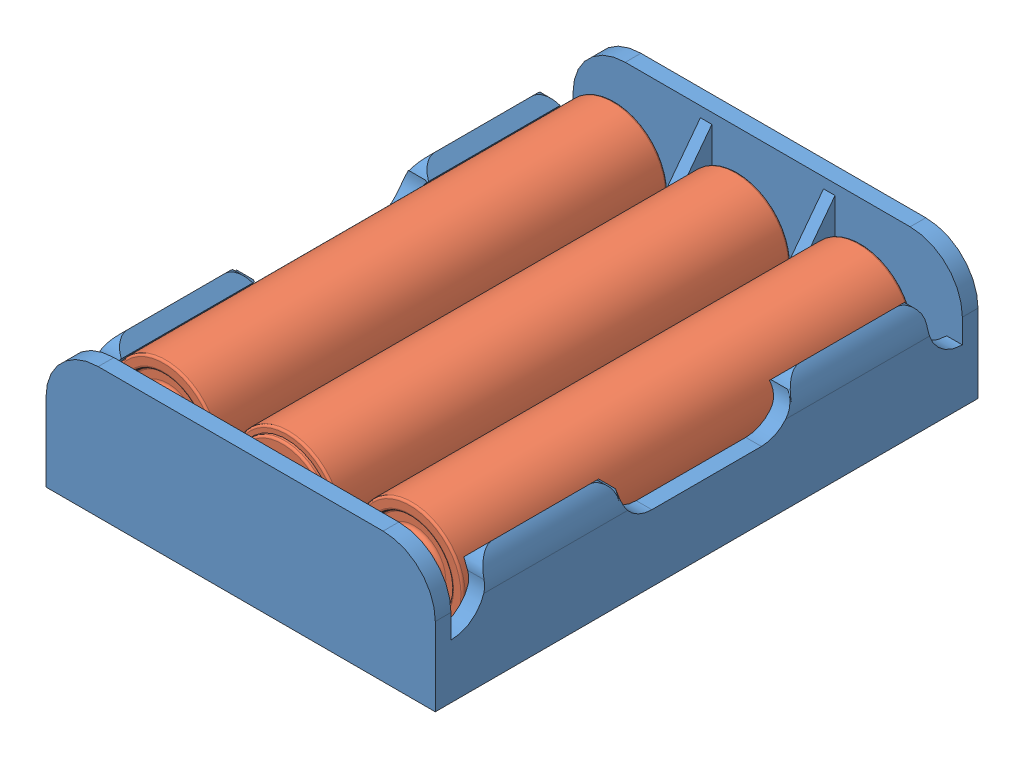
SolidWorks assembly Assemblage Coupleur piles, configuration Défaut. Lengths in mm.
Overall size (37.3 13.3 52).
4 component instances, 2 part files, 6 mates.
Components (placement in the parent):
- Coupleur piles-1: Coupleur piles [Défaut] at (3.7498 -7.3458 52) size (37.3 12.5 52)
- Pile-1: Pile [Défaut] at (-8.0261 -0.7458 30.4) x (0.997428 0.07167 0) z (0.07167 -0.997428 0) size (10.2 44.7 10.2)
- Pile-2: Pile [Défaut] at (3.7498 -0.7458 73.6) x (0.990016 -0.140952 0) z (0.140952 0.990016 0) size (10.2 44.7 10.2)
- Pile-4: Pile [Défaut] at (15.562 -0.7458 30.4) x (-0.925888 0.377799 0) z (0.377799 0.925888 0) size (10.2 44.7 10.2)
Mates (geometry in assembly coordinates):
- Tangent1: tangent anti-aligned: plane of Coupleur piles-1 through (3.7498 -5.8458 52) normal (0 1 0); cylinder of Pile-1 through (-8.0261 -0.7458 73.6) axis (0 0 -1) radius 5.1
- Distance1: distance = 2.5 mm anti-aligned: plane of Coupleur piles-1 through (17.3998 0.1542 27.5) normal (0 0 1); plane of Pile-1 through (-8.0261 -0.7458 30) normal (0 0 -1)
- Tangent2: tangent anti-aligned: plane of Coupleur piles-1 through (3.7498 -5.8458 52) normal (0 1 0); cylinder of Pile-2 through (3.7498 -0.7458 30.4) axis (0 0 1) radius 5.1
- Distance2: distance = 2.5 mm anti-aligned: plane of Coupleur piles-1 through (-9.9002 0.1542 76.5) normal (0 0 -1); plane of Pile-2 through (3.7498 -0.7458 74) normal (0 0 1)
- Tangent4: tangent anti-aligned: plane of Coupleur piles-1 through (3.7498 -5.8458 52) normal (0 1 0); cylinder of Pile-4 through (15.562 -0.7458 73.6) axis (0 0 -1) radius 5.1
- Distance4: distance = 2.5 mm anti-aligned: plane of Coupleur piles-1 through (17.3998 0.1542 27.5) normal (0 0 1); plane of Pile-4 through (15.562 -0.7458 30) normal (0 0 -1)
